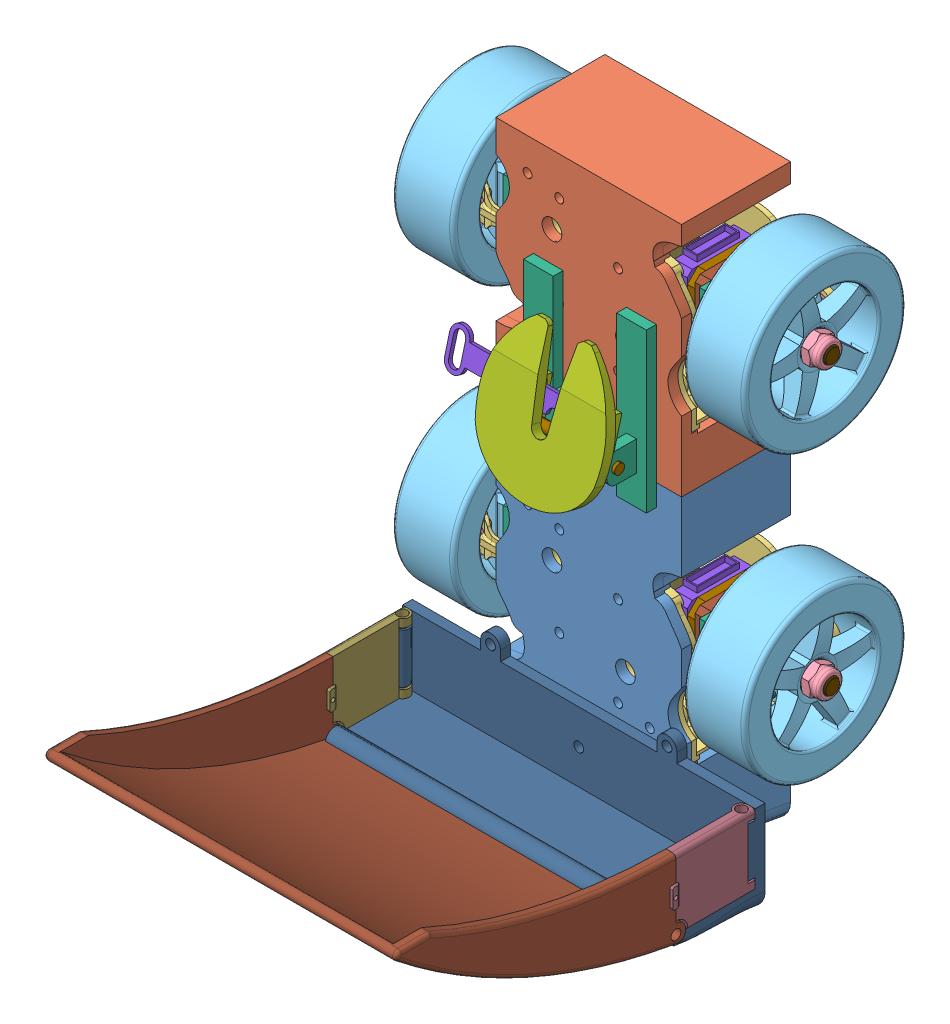
SolidWorks assembly Chassis assembly 2 - kopie, configuration Default. Lengths in mm.
Overall size (185.37 297.4 273.69).
160 component instances, 31 part files, 33 mates.
Components (placement in the parent):
- Dolly chassis half 1-1: Dolly chassis half 1 [Default] at (2.6348 264.5467 189.9496) size (93.68 170.93 55)
- Dolly chassis half 2-1: Dolly chassis half 2 [Default] at (2.6348 264.5467 189.9496) size (93.68 119.07 55)
- Module Assembly-1: Module Assembly [Default] at (-63.8652 93.3967 162.4496) x (0 -1 0) z (-1 0 0) size (68.25 51.28 97.81)
  - Housing-1: Housing [Default] at origin size (64.25 48.5 67.91)
  - Bearing 12x8-1: Bearing 12x8 [Default] at (0 -18.25 0.75) x (-0.914388 0 0.40484) z (-0.40484 0 -0.914388) size (12 3.5 12)
  - Spindle-1: Spindle [Default] at (0 2 0.75) size (49.04 45 20.5)
  - Spindle base-1: Spindle base [Default] at (0 2 -15.25) x (-1 0 0) z (0 -1 0) size (37.62 3.5 44.8)
  - Encoder-1: Encoder [Défaut] at (0 2 -12.48) x (0 1 0) z (0 0 1) size (28.68 37.25 10.4)
  - Wheel-1: Wheel [Default] at (0 2 -8.55) x (0.929787 0.368098 0) z (0.368098 -0.929787 0) size (81.5 31 81.5) (hidden)
  - Stepper Nema14-1: Stepper Nema14 [Predeterminado] at (4.764 -15.5 -30.1157) x (-1 0 0) z (0 1 0) size (37.8 40 35)
    - nema14_base-1: nema14_base [Predeterminado] at (-12.736 -8.6343 35) size (37.8 9 35)
    - nema14_centro-1: nema14_centro [Predeterminado] at (-12.736 0.3657 35) size (35 4 35)
    - nema14_eje-1: nema14_eje [Predeterminado] at (4.764 -6.6343 17.5) x (0 1 0) z (-0.939004 0 0.343907) size (38 5 5)
    - nema14_techo-1: nema14_techo [Predeterminado] at (-12.736 4.3657 35) size (35 9 35)
  - Servo motor-1: Servo motor [Default] at (-25.7048 26.288 -66.0832) x (0 0 1) z (1 0 0) size (11.5 29.2 32.5) (flexible)
    - TowerPro-SG90-Body-1: TowerPro-SG90-Body [Default] at (13.6721 7.288 30.7048) size (11.5 26 32.5)
    - ServoFinalGear-1: ServoFinalGear [Default] at (13.6721 33.288 25.7048) x (0.607544 0 -0.794286) z (0.794286 0 0.607544) size (4.64 3.2 4.64)
  - Control arm-1: Control arm [Default] at (0 -7.5 -52.4111) x (0.891007 0 0.45399) z (0.45399 0 -0.891007) size (37.9 4.5 7.8)
  - Ball joint assy-1: Ball joint assy [Default] at (-26.7302 -5 -12.8697) x (-0.874356 0 0.485286) z (0.485286 0 0.874356) size (15.43 16.21 22.24) (flexible)
    - Ball-1: Ball [Default] at origin size (5.5 15.11 5.5)
    - Joint-1: Joint [Default] at (-3.8823 13.66 -6.9948) x (0.874356 0 -0.485286) z (0 -1 0) size (5.1 22.6 5.1)
  - Ball joint assy-2: Ball joint assy [Default] at (-26.7302 -5 -66.0308) x (-0.846813 0 0.531891) z (0.531891 0 0.846813) size (16.34 16.21 21.85) (flexible)
    - Ball-1: Ball [Default] at origin size (5.5 15.11 5.5)
    - Joint-1: Joint [Default] at (4.2551 13.66 6.7745) x (-0.846813 0 0.531891) z (0 -1 0) size (5.1 22.6 5.1)
  - Steering rod-1: Steering rod [Default] at (-26.7302 -18.66 -18.4608) x (-0.014502 0.999895 0) z (-0.999895 -0.014502 0) size (3 28.27 3)
  - Wheel adapter-1: Wheel adapter [Default] at (0 2 -13.8175) x (0.291296 -0.956633 0) z (-0.956633 -0.291296 0) size (8.34 40 8.37)
  - Wheel spacer-1: Wheel spacer [Default] at (0 2 12.25) x (0.368098 -0.929787 0) z (0.929787 0.368098 0) size (13.86 8 12)
  - M3x5 din 7984-1: M3x5 din 7984 [Default] at (15.31 20.9 -16.25) x (0.933505 0.358563 0) z (0 0 -1) size (5.5 5.5 7)
  - Housing lid-1: Housing lid [Default] at (0 4 0) x (-1 0 0) z (0 0 1) size (68.25 9.28 69.91)
  - Bearing 12x8-3: Bearing 12x8 [Default] at (0 22.25 0.75) x (-0.914388 0 0.40484) z (0.40484 0 0.914388) size (12 3.5 12)
  - M8 nut-1: M8 nut [Default] at (0 2 16.6825) x (-0.817347 -0.576146 0) z (0 0 1) size (13 16.06 8.5)
  - M3x5 din 7984-2: M3x5 din 7984 [Default] at (15.31 -16.9 -16.25) x (-0.933505 0.358563 0) z (0 0 -1) size (5.5 5.5 7)
  - M3x5 din 7984-3: M3x5 din 7984 [Default] at (-15.31 20.9 -16.25) x (0.933505 -0.358563 0) z (0 0 -1) size (5.5 5.5 7)
  - M3x5 din 7984-4: M3x5 din 7984 [Default] at (-15.31 -16.9 -16.25) x (-0.933505 -0.358563 0) z (0 0 -1) size (5.5 5.5 7)
  - M3x5 din 7984-5: M3x5 din 7984 [Default] at (-13 15 -17.75) x (0.999849 0.017374 0) z (0 0 1) size (5.5 5.5 7)
  - M3x5 din 7984-6: M3x5 din 7984 [Default] at (-13 -11 -17.75) x (-0.999849 0.017374 0) z (0 0 1) size (5.5 5.5 7)
  - M3x5 din 7984-7: M3x5 din 7984 [Default] at (13 15 -17.75) x (0.999849 -0.017374 0) z (0 0 1) size (5.5 5.5 7)
  - M3x5 din 7984-8: M3x5 din 7984 [Default] at (13 -11 -17.75) x (-0.999849 -0.017374 0) z (0 0 1) size (5.5 5.5 7)
- Module Assembly-2: Module Assembly [Default] at (69.1348 93.3967 162.4496) x (0 1 0) z (1 0 0) size (68.25 51.28 97.81)
  - Housing-1: Housing [Default] at origin size (64.25 48.5 67.91)
  - Bearing 12x8-1: Bearing 12x8 [Default] at (0 -18.25 0.75) x (-0.914388 0 0.40484) z (-0.40484 0 -0.914388) size (12 3.5 12)
  - Spindle-1: Spindle [Default] at (0 2 0.75) size (49.04 45 20.5)
  - Spindle base-1: Spindle base [Default] at (0 2 -15.25) x (-1 0 0) z (0 -1 0) size (37.62 3.5 44.8)
  - Encoder-1: Encoder [Défaut] at (0 2 -12.48) x (0 1 0) z (0 0 1) size (28.68 37.25 10.4)
  - Wheel-1: Wheel [Default] at (0 2 -8.55) x (0.929787 0.368098 0) z (0.368098 -0.929787 0) size (81.5 31 81.5) (hidden)
  - Stepper Nema14-1: Stepper Nema14 [Predeterminado] at (4.764 -15.5 -30.1157) x (-1 0 0) z (0 1 0) size (37.8 40 35)
    - nema14_base-1: nema14_base [Predeterminado] at (-12.736 -8.6343 35) size (37.8 9 35)
    - nema14_centro-1: nema14_centro [Predeterminado] at (-12.736 0.3657 35) size (35 4 35)
    - nema14_eje-1: nema14_eje [Predeterminado] at (4.764 -6.6343 17.5) x (0 1 0) z (-0.939004 0 0.343907) size (38 5 5)
    - nema14_techo-1: nema14_techo [Predeterminado] at (-12.736 4.3657 35) size (35 9 35)
  - Servo motor-1: Servo motor [Default] at (-25.7048 26.288 -66.0832) x (0 0 1) z (1 0 0) size (11.5 29.2 32.5) (flexible)
    - TowerPro-SG90-Body-1: TowerPro-SG90-Body [Default] at (13.6721 7.288 30.7048) size (11.5 26 32.5)
    - ServoFinalGear-1: ServoFinalGear [Default] at (13.6721 33.288 25.7048) x (0.607544 0 -0.794286) z (0.794286 0 0.607544) size (4.64 3.2 4.64)
  - Control arm-1: Control arm [Default] at (0 -7.5 -52.4111) x (0.891007 0 0.45399) z (0.45399 0 -0.891007) size (37.9 4.5 7.8)
  - Ball joint assy-1: Ball joint assy [Default] at (-26.7302 -5 -12.8697) x (-0.874356 0 0.485286) z (0.485286 0 0.874356) size (15.43 16.21 22.24) (flexible)
    - Ball-1: Ball [Default] at origin size (5.5 15.11 5.5)
    - Joint-1: Joint [Default] at (-3.8823 13.66 -6.9948) x (0.874356 0 -0.485286) z (0 -1 0) size (5.1 22.6 5.1)
  - Ball joint assy-2: Ball joint assy [Default] at (-26.7302 -5 -66.0308) x (-0.846813 0 0.531891) z (0.531891 0 0.846813) size (16.34 16.21 21.85) (flexible)
    - Ball-1: Ball [Default] at origin size (5.5 15.11 5.5)
    - Joint-1: Joint [Default] at (4.2551 13.66 6.7745) x (-0.846813 0 0.531891) z (0 -1 0) size (5.1 22.6 5.1)
  - Steering rod-1: Steering rod [Default] at (-26.7302 -18.66 -18.4608) x (-0.014502 0.999895 0) z (-0.999895 -0.014502 0) size (3 28.27 3)
  - Wheel adapter-1: Wheel adapter [Default] at (0 2 -13.8175) x (0.291296 -0.956633 0) z (-0.956633 -0.291296 0) size (8.34 40 8.37)
  - Wheel spacer-1: Wheel spacer [Default] at (0 2 12.25) x (0.368098 -0.929787 0) z (0.929787 0.368098 0) size (13.86 8 12)
  - M3x5 din 7984-1: M3x5 din 7984 [Default] at (15.31 20.9 -16.25) x (0.933505 0.358563 0) z (0 0 -1) size (5.5 5.5 7)
  - Housing lid-1: Housing lid [Default] at (0 4 0) x (-1 0 0) z (0 0 1) size (68.25 9.28 69.91)
  - Bearing 12x8-3: Bearing 12x8 [Default] at (0 22.25 0.75) x (-0.914388 0 0.40484) z (0.40484 0 0.914388) size (12 3.5 12)
  - M8 nut-1: M8 nut [Default] at (0 2 16.6825) x (-0.817347 -0.576146 0) z (0 0 1) size (13 16.06 8.5)
  - M3x5 din 7984-2: M3x5 din 7984 [Default] at (15.31 -16.9 -16.25) x (-0.933505 0.358563 0) z (0 0 -1) size (5.5 5.5 7)
  - M3x5 din 7984-3: M3x5 din 7984 [Default] at (-15.31 20.9 -16.25) x (0.933505 -0.358563 0) z (0 0 -1) size (5.5 5.5 7)
  - M3x5 din 7984-4: M3x5 din 7984 [Default] at (-15.31 -16.9 -16.25) x (-0.933505 -0.358563 0) z (0 0 -1) size (5.5 5.5 7)
  - M3x5 din 7984-5: M3x5 din 7984 [Default] at (-13 15 -17.75) x (0.999849 0.017374 0) z (0 0 1) size (5.5 5.5 7)
  - M3x5 din 7984-6: M3x5 din 7984 [Default] at (-13 -11 -17.75) x (-0.999849 0.017374 0) z (0 0 1) size (5.5 5.5 7)
  - M3x5 din 7984-7: M3x5 din 7984 [Default] at (13 15 -17.75) x (0.999849 -0.017374 0) z (0 0 1) size (5.5 5.5 7)
  - M3x5 din 7984-8: M3x5 din 7984 [Default] at (13 -11 -17.75) x (-0.999849 -0.017374 0) z (0 0 1) size (5.5 5.5 7)
- Module Assembly-3: Module Assembly [Default] at (69.1348 238.0467 162.4496) x (0 1 0) z (1 0 0) size (68.25 51.28 97.81)
  - Housing-1: Housing [Default] at origin size (64.25 48.5 67.91)
  - Bearing 12x8-1: Bearing 12x8 [Default] at (0 -18.25 0.75) x (-0.914388 0 0.40484) z (-0.40484 0 -0.914388) size (12 3.5 12)
  - Spindle-1: Spindle [Default] at (0 2 0.75) size (49.04 45 20.5)
  - Spindle base-1: Spindle base [Default] at (0 2 -15.25) x (-1 0 0) z (0 -1 0) size (37.62 3.5 44.8)
  - Encoder-1: Encoder [Défaut] at (0 2 -12.48) x (0 1 0) z (0 0 1) size (28.68 37.25 10.4)
  - Wheel-1: Wheel [Default] at (0 2 -8.55) x (0.929787 0.368098 0) z (0.368098 -0.929787 0) size (81.5 31 81.5) (hidden)
  - Stepper Nema14-1: Stepper Nema14 [Predeterminado] at (4.764 -15.5 -30.1157) x (-1 0 0) z (0 1 0) size (37.8 40 35)
    - nema14_base-1: nema14_base [Predeterminado] at (-12.736 -8.6343 35) size (37.8 9 35)
    - nema14_centro-1: nema14_centro [Predeterminado] at (-12.736 0.3657 35) size (35 4 35)
    - nema14_eje-1: nema14_eje [Predeterminado] at (4.764 -6.6343 17.5) x (0 1 0) z (-0.939004 0 0.343907) size (38 5 5)
    - nema14_techo-1: nema14_techo [Predeterminado] at (-12.736 4.3657 35) size (35 9 35)
  - Servo motor-1: Servo motor [Default] at (-25.7048 26.288 -66.0832) x (0 0 1) z (1 0 0) size (11.5 29.2 32.5) (flexible)
    - TowerPro-SG90-Body-1: TowerPro-SG90-Body [Default] at (13.6721 7.288 30.7048) size (11.5 26 32.5)
    - ServoFinalGear-1: ServoFinalGear [Default] at (13.6721 33.288 25.7048) x (0.607544 0 -0.794286) z (0.794286 0 0.607544) size (4.64 3.2 4.64)
  - Control arm-1: Control arm [Default] at (0 -7.5 -52.4111) x (0.891007 0 0.45399) z (0.45399 0 -0.891007) size (37.9 4.5 7.8)
  - Ball joint assy-1: Ball joint assy [Default] at (-26.7302 -5 -12.8697) x (-0.874356 0 0.485286) z (0.485286 0 0.874356) size (15.43 16.21 22.24) (flexible)
    - Ball-1: Ball [Default] at origin size (5.5 15.11 5.5)
    - Joint-1: Joint [Default] at (-3.8823 13.66 -6.9948) x (0.874356 0 -0.485286) z (0 -1 0) size (5.1 22.6 5.1)
  - Ball joint assy-2: Ball joint assy [Default] at (-26.7302 -5 -66.0308) x (-0.846813 0 0.531891) z (0.531891 0 0.846813) size (16.34 16.21 21.85) (flexible)
    - Ball-1: Ball [Default] at origin size (5.5 15.11 5.5)
    - Joint-1: Joint [Default] at (4.2551 13.66 6.7745) x (-0.846813 0 0.531891) z (0 -1 0) size (5.1 22.6 5.1)
  - Steering rod-1: Steering rod [Default] at (-26.7302 -18.66 -18.4608) x (-0.014502 0.999895 0) z (-0.999895 -0.014502 0) size (3 28.27 3)
  - Wheel adapter-1: Wheel adapter [Default] at (0 2 -13.8175) x (0.291296 -0.956633 0) z (-0.956633 -0.291296 0) size (8.34 40 8.37)
  - Wheel spacer-1: Wheel spacer [Default] at (0 2 12.25) x (0.368098 -0.929787 0) z (0.929787 0.368098 0) size (13.86 8 12)
  - M3x5 din 7984-1: M3x5 din 7984 [Default] at (15.31 20.9 -16.25) x (0.933505 0.358563 0) z (0 0 -1) size (5.5 5.5 7)
  - Housing lid-1: Housing lid [Default] at (0 4 0) x (-1 0 0) z (0 0 1) size (68.25 9.28 69.91)
  - Bearing 12x8-3: Bearing 12x8 [Default] at (0 22.25 0.75) x (-0.914388 0 0.40484) z (0.40484 0 0.914388) size (12 3.5 12)
  - M8 nut-1: M8 nut [Default] at (0 2 16.6825) x (-0.817347 -0.576146 0) z (0 0 1) size (13 16.06 8.5)
  - M3x5 din 7984-2: M3x5 din 7984 [Default] at (15.31 -16.9 -16.25) x (-0.933505 0.358563 0) z (0 0 -1) size (5.5 5.5 7)
  - M3x5 din 7984-3: M3x5 din 7984 [Default] at (-15.31 20.9 -16.25) x (0.933505 -0.358563 0) z (0 0 -1) size (5.5 5.5 7)
  - M3x5 din 7984-4: M3x5 din 7984 [Default] at (-15.31 -16.9 -16.25) x (-0.933505 -0.358563 0) z (0 0 -1) size (5.5 5.5 7)
  - M3x5 din 7984-5: M3x5 din 7984 [Default] at (-13 15 -17.75) x (0.999849 0.017374 0) z (0 0 1) size (5.5 5.5 7)
  - M3x5 din 7984-6: M3x5 din 7984 [Default] at (-13 -11 -17.75) x (-0.999849 0.017374 0) z (0 0 1) size (5.5 5.5 7)
  - M3x5 din 7984-7: M3x5 din 7984 [Default] at (13 15 -17.75) x (0.999849 -0.017374 0) z (0 0 1) size (5.5 5.5 7)
  - M3x5 din 7984-8: M3x5 din 7984 [Default] at (13 -11 -17.75) x (-0.999849 -0.017374 0) z (0 0 1) size (5.5 5.5 7)
- Module Assembly-4: Module Assembly [Default] at (-63.8652 238.0467 162.4496) x (0 -1 0) z (-1 0 0) size (68.25 51.28 97.81)
  - Housing-1: Housing [Default] at origin size (64.25 48.5 67.91)
  - Bearing 12x8-1: Bearing 12x8 [Default] at (0 -18.25 0.75) x (-0.914388 0 0.40484) z (-0.40484 0 -0.914388) size (12 3.5 12)
  - Spindle-1: Spindle [Default] at (0 2 0.75) size (49.04 45 20.5)
  - Spindle base-1: Spindle base [Default] at (0 2 -15.25) x (-1 0 0) z (0 -1 0) size (37.62 3.5 44.8)
  - Encoder-1: Encoder [Défaut] at (0 2 -12.48) x (0 1 0) z (0 0 1) size (28.68 37.25 10.4)
  - Wheel-1: Wheel [Default] at (0 2 -8.55) x (0.929787 0.368098 0) z (0.368098 -0.929787 0) size (81.5 31 81.5) (hidden)
  - Stepper Nema14-1: Stepper Nema14 [Predeterminado] at (4.764 -15.5 -30.1157) x (-1 0 0) z (0 1 0) size (37.8 40 35)
    - nema14_base-1: nema14_base [Predeterminado] at (-12.736 -8.6343 35) size (37.8 9 35)
    - nema14_centro-1: nema14_centro [Predeterminado] at (-12.736 0.3657 35) size (35 4 35)
    - nema14_eje-1: nema14_eje [Predeterminado] at (4.764 -6.6343 17.5) x (0 1 0) z (-0.939004 0 0.343907) size (38 5 5)
    - nema14_techo-1: nema14_techo [Predeterminado] at (-12.736 4.3657 35) size (35 9 35)
  - Servo motor-1: Servo motor [Default] at (-25.7048 26.288 -66.0832) x (0 0 1) z (1 0 0) size (11.5 29.2 32.5) (flexible)
    - TowerPro-SG90-Body-1: TowerPro-SG90-Body [Default] at (13.6721 7.288 30.7048) size (11.5 26 32.5)
    - ServoFinalGear-1: ServoFinalGear [Default] at (13.6721 33.288 25.7048) x (0.607544 0 -0.794286) z (0.794286 0 0.607544) size (4.64 3.2 4.64)
  - Control arm-1: Control arm [Default] at (0 -7.5 -52.4111) x (0.891007 0 0.45399) z (0.45399 0 -0.891007) size (37.9 4.5 7.8)
  - Ball joint assy-1: Ball joint assy [Default] at (-26.7302 -5 -12.8697) x (-0.874356 0 0.485286) z (0.485286 0 0.874356) size (15.43 16.21 22.24) (flexible)
    - Ball-1: Ball [Default] at origin size (5.5 15.11 5.5)
    - Joint-1: Joint [Default] at (-3.8823 13.66 -6.9948) x (0.874356 0 -0.485286) z (0 -1 0) size (5.1 22.6 5.1)
  - Ball joint assy-2: Ball joint assy [Default] at (-26.7302 -5 -66.0308) x (-0.846813 0 0.531891) z (0.531891 0 0.846813) size (16.34 16.21 21.85) (flexible)
    - Ball-1: Ball [Default] at origin size (5.5 15.11 5.5)
    - Joint-1: Joint [Default] at (4.2551 13.66 6.7745) x (-0.846813 0 0.531891) z (0 -1 0) size (5.1 22.6 5.1)
  - Steering rod-1: Steering rod [Default] at (-26.7302 -18.66 -18.4608) x (-0.014502 0.999895 0) z (-0.999895 -0.014502 0) size (3 28.27 3)
  - Wheel adapter-1: Wheel adapter [Default] at (0 2 -13.8175) x (0.291296 -0.956633 0) z (-0.956633 -0.291296 0) size (8.34 40 8.37)
  - Wheel spacer-1: Wheel spacer [Default] at (0 2 12.25) x (0.368098 -0.929787 0) z (0.929787 0.368098 0) size (13.86 8 12)
  - M3x5 din 7984-1: M3x5 din 7984 [Default] at (15.31 20.9 -16.25) x (0.933505 0.358563 0) z (0 0 -1) size (5.5 5.5 7)
  - Housing lid-1: Housing lid [Default] at (0 4 0) x (-1 0 0) z (0 0 1) size (68.25 9.28 69.91)
  - Bearing 12x8-3: Bearing 12x8 [Default] at (0 22.25 0.75) x (-0.914388 0 0.40484) z (0.40484 0 0.914388) size (12 3.5 12)
  - M8 nut-1: M8 nut [Default] at (0 2 16.6825) x (-0.817347 -0.576146 0) z (0 0 1) size (13 16.06 8.5)
  - M3x5 din 7984-2: M3x5 din 7984 [Default] at (15.31 -16.9 -16.25) x (-0.933505 0.358563 0) z (0 0 -1) size (5.5 5.5 7)
  - M3x5 din 7984-3: M3x5 din 7984 [Default] at (-15.31 20.9 -16.25) x (0.933505 -0.358563 0) z (0 0 -1) size (5.5 5.5 7)
  - M3x5 din 7984-4: M3x5 din 7984 [Default] at (-15.31 -16.9 -16.25) x (-0.933505 -0.358563 0) z (0 0 -1) size (5.5 5.5 7)
  - M3x5 din 7984-5: M3x5 din 7984 [Default] at (-13 15 -17.75) x (0.999849 0.017374 0) z (0 0 1) size (5.5 5.5 7)
  - M3x5 din 7984-6: M3x5 din 7984 [Default] at (-13 -11 -17.75) x (-0.999849 0.017374 0) z (0 0 1) size (5.5 5.5 7)
  - M3x5 din 7984-7: M3x5 din 7984 [Default] at (13 15 -17.75) x (0.999849 -0.017374 0) z (0 0 1) size (5.5 5.5 7)
  - M3x5 din 7984-8: M3x5 din 7984 [Default] at (13 -11 -17.75) x (-0.999849 -0.017374 0) z (0 0 1) size (5.5 5.5 7)
- Wheel-1: Wheel [Default] at (60.5848 93.3967 164.4496) x (0 0.146111 0.989268) z (0 0.989268 -0.146111) size (81.5 31 81.5)
- Wheel-2: Wheel [Default] at (60.5848 238.0467 164.4496) x (0 0.783676 -0.62117) z (0 -0.62117 -0.783676) size (81.5 31 81.5)
- Wheel-3: Wheel [Default] at (-55.3152 238.0467 164.4496) x (0 -0.929787 0.368098) z (0 -0.368098 -0.929787) size (81.5 31 81.5)
- Wheel-4: Wheel [Default] at (-55.3152 93.3967 164.4496) x (0 -0.783676 -0.62117) z (0 0.62117 -0.783676) size (81.5 31 81.5)
- Fifth_wheel_assembly-1: Fifth_wheel_assembly [Default] at (29.8333 135.1631 149.1448) x (-1 0 0) z (0 1 0) size (87.87 41.74 87.97)
  - Fifth_wheel_mount-1: Fifth_wheel_mount [Default] at (-6.9031 48.3048 102.7348) size (62 20 80)
  - Fifth_wheel_disk-1: Fifth_wheel_disk [Default] at (-5.9031 71.3457 44.4932) x (1 0 0) z (0 -0.255937 0.966694) size (66.74 23.06 75.99)
  - Fifth_wheel_kingpin-1: Fifth_wheel_kingpin [Default] at (-1.4031 62.5809 65.8769) x (1 0 0) z (0 -0.255937 0.966694) size (80 2 20)
  - Fifth_wheel_axle-1: Fifth_wheel_axle [Default] at (51.5969 60.8048 45.2348) x (0 0.948415 -0.31703) z (1 0 0) size (5 5 55)
- front assembly 2-1: front assembly 2 [Default] at (-66.6863 167.1407 117.1017) x (1 0 0) z (0 -1 0) size (181 187.95 76.47)
  - Foldable front base 2-1: Foldable front base 2 [Default] at (158.3211 77.8479 159.546) size (179.15 52.01 59.18)
  - foldable front flap 2-1: foldable front flap 2 [Default] at (69.3211 122.8479 151.0232) x (-1 0 0) z (0 0 -1) size (178.61 145.94 67.36)
  - Foldable front side flap right 2-1: Foldable front side flap right 2 [Default] at (-17.1789 86.3479 110.946) x (0 0 1) z (-1 0 0) size (35 43 8.5)
  - Foldable front side flap left 2-1: Foldable front side flap left 2 [Default] at (155.8211 86.3479 145.946) x (0 0 -1) z (1 0 0) size (35 43 8.5)
Mates (geometry in assembly coordinates):
- Coincident1: coincident: plane of Dolly chassis half 1-1 through (-44.2041 168.828 -11.5535) normal (0 1 0); plane of Dolly chassis half 2-1 through (-44.2041 168.828 -67.8767) normal (0 -1 0)
- Coincident2: coincident: plane of Dolly chassis half 1-1 through (2.6348 264.5467 194.9496) normal (0 0 1); plane of Dolly chassis half 2-1 through (2.6348 264.5467 194.9496) normal (0 0 1)
- Coincident3: coincident: plane of Dolly chassis half 1-1 through (49.4737 264.5467 194.9496) normal (1 0 0); plane of Dolly chassis half 2-1 through (49.4737 264.5467 194.9496) normal (1 0 0)
- Concentric1: concentric: cylinder of Dolly chassis half 1-1 through (-15.9041 108.4967 199.9496) axis (0 0 -1) radius 5; cylinder of Module Assembly-1/Housing lid-1 through (-15.9041 108.4967 179.9496) axis (0 0 1) radius 5
- Coincident4: coincident: plane of Dolly chassis half 1-1 through (2.6348 264.5467 189.9496) normal (0 0 -1); plane of Module Assembly-1/Housing lid-1 through (-63.8652 93.3967 189.9496) normal (0 0 1)
- Coincident5: coincident: plane of Dolly chassis half 1-1 through (-44.2041 264.5467 194.9496) normal (-1 0 0); plane of Module Assembly-1/Housing lid-1 through (-44.2041 93.3967 187.4496) normal (-1 0 0)
- Concentric2: concentric: cylinder of Dolly chassis half 1-1 through (21.1737 78.2967 199.9496) axis (0 0 -1) radius 5; cylinder of Module Assembly-2/Housing lid-1 through (21.1737 78.2967 179.9496) axis (0 0 1) radius 5
- Coincident6: coincident: plane of Dolly chassis half 1-1 through (49.4737 119.8967 194.9496) normal (1 0 0); plane of Module Assembly-2/Housing lid-1 through (49.4737 93.3967 187.4496) normal (1 0 0)
- Coincident7: coincident: plane of Dolly chassis half 1-1 through (2.6348 264.5467 189.9496) normal (0 0 -1); plane of Module Assembly-2/Housing lid-1 through (69.1348 93.3967 189.9496) normal (0 0 1)
- Concentric3: concentric: cylinder of Dolly chassis half 2-1 through (21.1737 222.9467 199.9496) axis (0 0 -1) radius 5; cylinder of Module Assembly-3/Housing lid-1 through (21.1737 222.9467 179.9496) axis (0 0 1) radius 5
- Coincident8: coincident: plane of Dolly chassis half 2-1 through (2.6348 264.5467 189.9496) normal (0 0 -1); plane of Module Assembly-3/Housing lid-1 through (69.1348 238.0467 189.9496) normal (0 0 1)
- Coincident9: coincident: plane of Dolly chassis half 2-1 through (49.4737 264.5467 194.9496) normal (1 0 0); plane of Module Assembly-3/Housing lid-1 through (49.4737 238.0467 187.4496) normal (1 0 0)
- Concentric4: concentric: cylinder of Dolly chassis half 2-1 through (-15.9041 253.1467 199.9496) axis (0 0 -1) radius 5; cylinder of Module Assembly-4/Housing lid-1 through (-15.9041 253.1467 179.9496) axis (0 0 1) radius 5
- Coincident10: coincident: plane of Dolly chassis half 2-1 through (-44.2041 264.5467 194.9496) normal (-1 0 0); plane of Module Assembly-4/Housing lid-1 through (-44.2041 238.0467 187.4496) normal (-1 0 0)
- Coincident11: coincident: plane of Dolly chassis half 1-1 through (2.6348 264.5467 189.9496) normal (0 0 -1); plane of Module Assembly-4/Housing lid-1 through (-63.8652 238.0467 189.9496) normal (0 0 1)
- Concentric5: concentric: cylinder of Module Assembly-2/Wheel adapter-1 through (55.3173 93.3967 164.4496) axis (-1 0 0) radius 4; cylinder of Wheel-1 through (60.5848 93.3967 164.4496) axis (1 0 0) radius 4
- Coincident15: coincident: plane of Module Assembly-2/Wheel spacer-1 through (73.3848 90.8464 170.8913) normal (0 0.146111 0.989268); plane of Wheel-1 through (81.3848 90.8464 170.8913) normal (0 -0.146111 -0.989268)
- Coincident16: coincident: plane of Module Assembly-2/Wheel spacer-1 through (81.3848 93.3967 164.4496) normal (1 0 0); plane of Wheel-1 through (81.3848 93.3967 164.4496) normal (-1 0 0)
- Concentric6: concentric: cylinder of Module Assembly-3/Wheel adapter-1 through (55.3173 238.0467 164.4496) axis (-1 0 0) radius 4; cylinder of Wheel-2 through (60.5848 238.0467 164.4496) axis (1 0 0) radius 4
- Coincident17: coincident: plane of Module Assembly-3/Wheel spacer-1 through (73.3848 235.4964 170.8913) normal (0 0.146111 0.989268); plane of Wheel-2 through (81.3848 235.4964 170.8913) normal (0 -0.146111 -0.989268)
- Coincident18: coincident: plane of Module Assembly-3/Wheel spacer-1 through (81.3848 238.0467 164.4496) normal (1 0 0); plane of Wheel-2 through (81.3848 238.0467 164.4496) normal (-1 0 0)
- Concentric7: concentric: cylinder of Module Assembly-4/Wheel adapter-1 through (-50.0477 238.0467 164.4496) axis (1 0 0) radius 4; cylinder of Wheel-3 through (-55.3152 238.0467 164.4496) axis (-1 0 0) radius 4
- Coincident19: coincident: plane of Module Assembly-4/Wheel spacer-1 through (-68.1152 240.5969 170.8913) normal (0 -0.146111 0.989268); plane of Wheel-3 through (-76.1152 240.5969 170.8913) normal (0 0.146111 -0.989268)
- Coincident20: coincident: plane of Module Assembly-4/Wheel spacer-1 through (-76.1152 238.0467 164.4496) normal (-1 0 0); plane of Wheel-3 through (-76.1152 238.0467 164.4496) normal (1 0 0)
- Concentric8: concentric: cylinder of Module Assembly-1/Wheel adapter-1 through (-50.0477 93.3967 164.4496) axis (1 0 0) radius 4; cylinder of Wheel-4 through (-55.3152 93.3967 164.4496) axis (-1 0 0) radius 4
- Coincident21: coincident: plane of Module Assembly-1/Wheel spacer-1 through (-68.1152 95.9469 170.8913) normal (0 -0.146111 0.989268); plane of Wheel-4 through (-76.1152 95.9469 170.8913) normal (0 0.146111 -0.989268)
- Coincident22: coincident: plane of Module Assembly-1/Wheel spacer-1 through (-76.1152 93.3967 164.4496) normal (-1 0 0); plane of Wheel-4 through (-76.1152 93.3967 164.4496) normal (1 0 0)
- Coincident23: coincident: plane of Dolly chassis half 2-1 through (2.6348 264.5467 194.9496) normal (0 0 1); plane of Fifth_wheel_assembly-1/Fifth_wheel_mount-1 through (36.7364 237.898 194.9496) normal (0 0 -1)
- Parallel2: parallel: plane of Dolly chassis half 2-1 through (2.6348 287.898 189.9496) normal (0 1 0); plane of Fifth_wheel_assembly-1/Fifth_wheel_mount-1 through (36.7364 237.898 199.9496) normal (0 1 0)
- Distance1: distance = 50 mm: plane of Fifth_wheel_assembly-1/Fifth_wheel_mount-1 through (36.7364 237.898 199.9496) normal (0 1 0); plane of Dolly chassis half 2-1 through (2.6348 287.898 189.9496) normal (0 1 0)
- Coincident24: coincident: plane of Dolly chassis half 1-1 through (2.6348 264.5467 194.9496) normal (0 0 1); plane of front assembly 2-1/Foldable front base 2-1 through (89.8366 7.5946 194.9496) normal (0 0 -1)
- Coincident25: coincident: line of Dolly chassis half 1-1 through (39.4737 7.5946 194.9496) axis (-1 0 0); line of front assembly 2-1/Foldable front base 2-1 through (-78.1634 7.5946 194.9496) axis (1 0 0)
- Coincident29: coincident: moEndPointRef_w of Dolly chassis half 1-1; moEndPointRef_w of front assembly 2-1/Foldable front base 2-1
